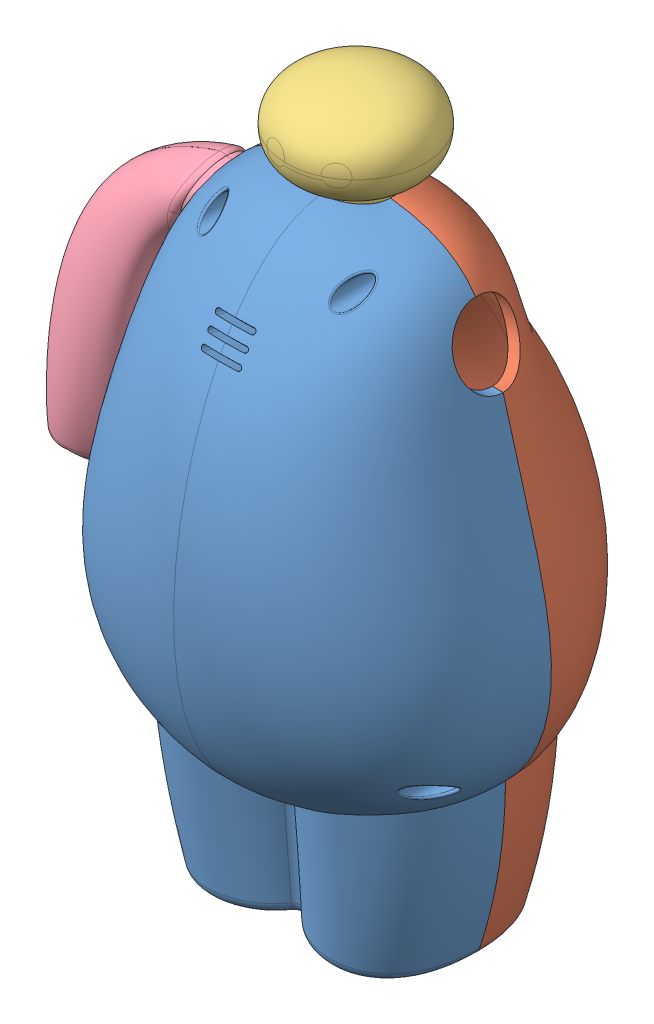
SolidWorks assembly baymax, configuration Default. Lengths in mm.
Overall size (145.05 203.48 105.18).
4 component instances, 4 part files, 4 mates.
Components (placement in the parent):
- body_back-1: body_back [Default] at (-6.2154 -3.7223 -22.941) size (115.03 178.98 59.07)
- body_front-1: body_front [Default] at (-6.2154 -3.7223 -22.941) size (113.65 177.95 55.91)
- head-1: head [Default] at (-6.2154 81.8529 -22.941) x (-0.981308 0 0.192443) z (-0.192443 0 -0.981308) size (40 29 40)
- arm-1: arm [Default] at (-43.32 62.5097 -22.927) size (55.74 91.33 29.66)
Mates (geometry in assembly coordinates):
- Coincident1: coincident anti-aligned: plane of body_back-1 through (-6.2154 -3.7223 -22.941) normal (0 0 -1); plane of body_front-1 through (-6.2154 -3.7223 -22.941) normal (0 0 1)
- Coincident2: coincident aligned: plane of body_back-1 through (15.3768 -92.6223 -47.012) normal (0 -1 0); plane of body_front-1 through (15.3768 -92.6223 -47.012) normal (0 -1 0)
- Coincident3: coincident aligned: plane of body_back-1 through (15.2346 -79.4473 -22.941) normal (-1 0 0); plane of body_front-1 through (15.2346 -79.4473 -22.941) normal (-1 0 0)
- Concentric1: concentric anti-aligned: cylinder of body_back-1 through (-6.2154 63.6524 -22.941) axis (0 1 0) radius 10; cylinder of head-1 through (-6.2154 89.8529 -22.941) axis (0 -1 0) radius 9
